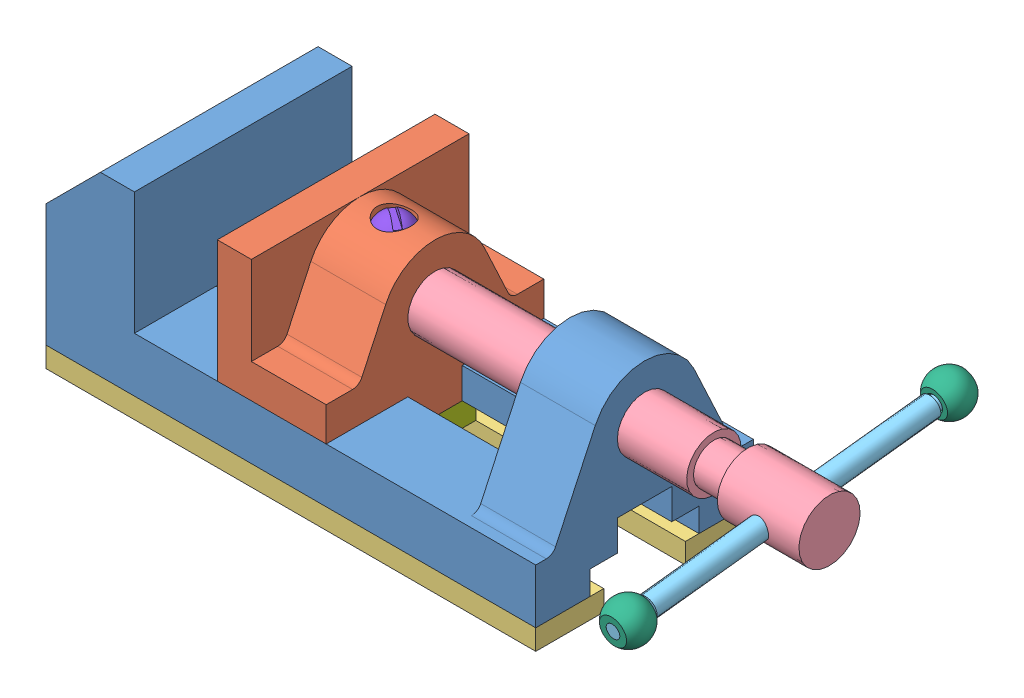
SolidWorks assembly Bench Vice Assembly, configuration Default. Lengths in mm.
Overall size (198.38 59.48 104.83).
16 component instances, 10 part files, 33 mates.
Components (placement in the parent):
- Base-1: Base [Default] at (-18.0833 52.9448 107.8649) size (144 52 64)
- Vice Jaw-1: Vice Jaw [Default] at (32.2926 68.9448 107.8649) size (32 45 64)
- Base Plate-1: Base Plate [Default] at (53.9167 49.9448 129.8649) x (1 0 0) z (0 -1 0) size (144 20 6)
- Base Plate-2: Base Plate [Default] at (53.9167 49.9448 85.8649) x (1 0 0) z (0 -1 0) size (144 20 6)
- Jaw screw-1: Jaw screw [Default] at (42.2926 88.9448 107.8649) x (1 0 0) z (0 0.204055 -0.978959) size (138 18 18)
- Screw Bar-1: Screw Bar [Default] at (168.2926 88.9448 107.8649) x (-0.780782 0.620739 0.07115) z (0 0.113876 -0.993495) size (6 6 104)
- Bar Globes-1: Bar Globes [Default] at (168.302 77.5627 154.3713) x (0 -0.113876 0.993495) z (-0.999999 -0.00156 -0.000179) size (9 12 12)
- Bar Globes-4: Bar Globes [Default] at (162.4418 92.9794 60.5163) x (0 0.113876 -0.993495) z (0.230117 -0.966833 -0.11082) size (9 12 12)
- Clamping Plate-1: Clamping Plate [Default] at (48.2926 56.4448 107.8649) x (0 0 1) z (0 -1 0) size (24 32 7)
- Oval Fillister-1: Oval Fillister [Default] at (52.2926 92.9448 107.8649) x (0.566352 0 -0.824163) z (0.824163 0 0.566352) size (10 13.48 10)
- Set Screw 1-1: Set Screw 1 [Default] at (19.9167 64.6769 129.8649) x (1 0 0) z (0 0 -1) size (15 17.73 14.87)
- Set Screw 2-1: Set Screw 2 [Default] at (40.2926 77.6769 107.8649) x (1 0 0) z (0 0 -1) size (15 24.73 14.87)
- Set Screw 2-2: Set Screw 2 [Default] at (56.2926 77.6769 107.8649) x (0.982082 0 -0.188455) z (-0.188455 0 -0.982082) size (15 24.73 14.87)
- Set Screw 1-2: Set Screw 1 [Default] at (89.9167 64.6769 129.8649) x (0.982082 0 -0.188455) z (-0.188455 0 -0.982082) size (15 17.73 14.87)
- Set Screw 1-3: Set Screw 1 [Default] at (89.9167 64.6769 85.8649) x (0.918365 0 -0.395734) z (-0.395734 0 -0.918365) size (15 17.73 14.87)
- Set Screw 1-4: Set Screw 1 [Default] at (19.9167 64.6769 85.8649) x (0.8 0 -0.6) z (-0.6 0 -0.8) size (15 17.73 14.87)
Mates (geometry in assembly coordinates):
- Concentric1: concentric aligned: cylinder of Base-1 through (103.9167 88.9448 107.8649) axis (1 0 0) radius 8; cylinder of Vice Jaw-1 through (53.1719 88.9448 107.8649) axis (1 0 0) radius 6
- Coincident1: coincident anti-aligned: plane of Base-1 through (7.9167 68.9448 139.8649) normal (0 1 0); plane of Vice Jaw-1 through (45.1719 68.9448 139.8649) normal (0 -1 0)
- Concentric2: concentric aligned: cylinder of Base-1 through (19.9167 52.9448 129.8649) axis (0 -1 0) radius 3; cylinder of Base Plate-1 through (19.9167 46.9448 129.8649) axis (0 -1 0) radius 3.5
- Coincident2: coincident anti-aligned: plane of Base-1 through (-18.0833 52.9448 139.8649) normal (0 -1 0); plane of Base Plate-1 through (53.9167 52.9448 129.8649) normal (0 1 0)
- Concentric3: concentric aligned: cylinder of Base-1 through (89.9167 52.9448 129.8649) axis (0 -1 0) radius 3; circle of Base Plate-1
- Coincident3: coincident anti-aligned: plane of Base-1 through (-18.0833 52.9448 139.8649) normal (0 -1 0); plane of Base Plate-2 through (53.9167 52.9448 85.8649) normal (0 1 0)
- Concentric4: concentric aligned: cylinder of Base-1 through (19.9167 52.9448 85.8649) axis (0 -1 0) radius 3; cylinder of Base Plate-2 through (19.9167 46.9448 85.8649) axis (0 -1 0) radius 3.5
- Concentric5: concentric aligned: cylinder of Base-1 through (89.9167 52.9448 85.8649) axis (0 -1 0) radius 3; circle of Base Plate-2
- Concentric6: concentric anti-aligned: cylinder of Base-1 through (103.9167 88.9448 107.8649) axis (1 0 0) radius 8; cylinder of Jaw screw-1 through (46.2882 88.9448 107.8649) axis (-1 0 0) radius 8
- Coincident5: coincident anti-aligned: plane of Vice Jaw-1 through (77.1719 68.9448 139.8649) normal (1 0 0); plane of Jaw screw-1 through (77.1719 85.3113 112.6396) normal (-1 0 0)
- Concentric7: concentric anti-aligned: cylinder of Jaw screw-1 through (181.1719 81.3154 103.0909) axis (0 -0.847717 -0.530449) radius 3; cylinder of Screw Bar-1 through (181.1719 53.3408 85.586) axis (0 0.847717 0.530449) radius 3
- Width2: width: plane of Screw Bar-1; plane of Screw Bar-1; cylinder of Jaw screw-1 through (34.7756 88.9448 107.8649) axis (-1 0 0) radius 9
- Concentric8: concentric anti-aligned: cylinder of Screw Bar-1 through (181.1719 44.8636 80.2815) axis (0 0.847717 0.530449) radius 2; cylinder of Bar Globes-1 through (181.1719 125.3967 130.6742) axis (0 -0.847717 -0.530449) radius 2
- Coincident6: coincident aligned: plane of Screw Bar-1; plane of Bar Globes-1
- Concentric10: concentric aligned: cylinder of Screw Bar-1 through (181.1719 44.8636 80.2815) axis (0 0.847717 0.530449) radius 2; cylinder of Bar Globes-4 through (181.1719 52.493 85.0556) axis (0 0.847717 0.530449) radius 2
- Coincident9: coincident aligned: plane of Screw Bar-1; plane of Bar Globes-4
- Concentric11: concentric aligned: cylinder of Vice Jaw-1 through (53.1719 59.9448 107.8649) axis (0 -1 0) radius 3; cylinder of Clamping Plate-1 through (53.1719 52.9448 107.8649) axis (0 -1 0) radius 3.5
- Concentric12: concentric aligned: cylinder of Vice Jaw-1 through (69.1719 59.9448 107.8649) axis (0 -1 0) radius 3; cylinder of Clamping Plate-1 through (69.1719 52.9448 107.8649) axis (0 -1 0) radius 3.5
- Coincident10: coincident anti-aligned: plane of Vice Jaw-1 through (45.1719 59.9448 115.8649) normal (0 -1 0); plane of Clamping Plate-1 through (61.1719 59.9448 107.8649) normal (0 1 0)
- Concentric13: concentric aligned: cylinder of Vice Jaw-1 through (65.1719 104.9448 107.8649) axis (0 1 0) radius 3; cylinder of Oval Fillister-1 through (65.1719 106.2283 107.8649) axis (0 1 0) radius 3
- Coincident11: coincident anti-aligned: plane of Vice Jaw-1 through (68.1719 100.9448 107.8649) normal (0 1 0); plane of Oval Fillister-1 through (66.8709 100.9448 105.3924) normal (0 -1 0)
- Concentric14: concentric aligned: cylinder of Base Plate-1 through (19.9167 46.9448 129.8649) axis (0 -1 0) radius 3.5; cylinder of Set Screw 1-1 through (19.9167 46.9448 129.8649) axis (0 -1 0) radius 3
- Coincident12: coincident aligned: plane of Base Plate-1 through (53.9167 46.9448 129.8649) normal (0 -1 0); plane of Set Screw 1-1 through (27.4167 46.9448 129.8649) normal (0 -1 0)
- Concentric15: concentric aligned: cylinder of Vice Jaw-1 through (53.1719 59.9448 107.8649) axis (0 -1 0) radius 3; cylinder of Set Screw 2-1 through (53.1719 52.9448 107.8649) axis (0 -1 0) radius 3
- Coincident13: coincident aligned: plane of Clamping Plate-1 through (61.1719 52.9448 107.8649) normal (0 -1 0); plane of Set Screw 2-1 through (60.6719 52.9448 107.8649) normal (0 -1 0)
- Coincident14: coincident aligned: plane of Clamping Plate-1 through (61.1719 52.9448 107.8649) normal (0 -1 0); plane of Set Screw 2-2 through (76.5375 52.9448 106.4515) normal (0 -1 0)
- Concentric16: concentric aligned: cylinder of Clamping Plate-1 through (69.1719 52.9448 107.8649) axis (0 -1 0) radius 3.5; cylinder of Set Screw 2-2 through (69.1719 52.9448 107.8649) axis (0 -1 0) radius 3
- Coincident16: coincident aligned: plane of Base Plate-1 through (53.9167 46.9448 129.8649) normal (0 -1 0); plane of Set Screw 1-2 through (97.2823 46.9448 128.4515) normal (0 -1 0)
- Concentric17: concentric aligned: cylinder of Base-1 through (89.9167 52.9448 129.8649) axis (0 -1 0) radius 3; cylinder of Set Screw 1-2 through (89.9167 46.9448 129.8649) axis (0 -1 0) radius 3
- Coincident17: coincident aligned: plane of Base Plate-1 through (53.9167 46.9448 129.8649) normal (0 -1 0); plane of Set Screw 1-3 through (96.8045 46.9448 82.8969) normal (0 -1 0)
- Concentric18: concentric aligned: cylinder of Base-1 through (89.9167 52.9448 85.8649) axis (0 -1 0) radius 3; cylinder of Set Screw 1-3 through (89.9167 46.9448 85.8649) axis (0 -1 0) radius 3
- Coincident18: coincident aligned: plane of Base Plate-1 through (53.9167 46.9448 129.8649) normal (0 -1 0); plane of Set Screw 1-4 through (25.9167 46.9448 81.3649) normal (0 -1 0)
- Concentric19: concentric aligned: cylinder of Base-1 through (19.9167 52.9448 85.8649) axis (0 -1 0) radius 3; cylinder of Set Screw 1-4 through (19.9167 46.9448 85.8649) axis (0 -1 0) radius 3
